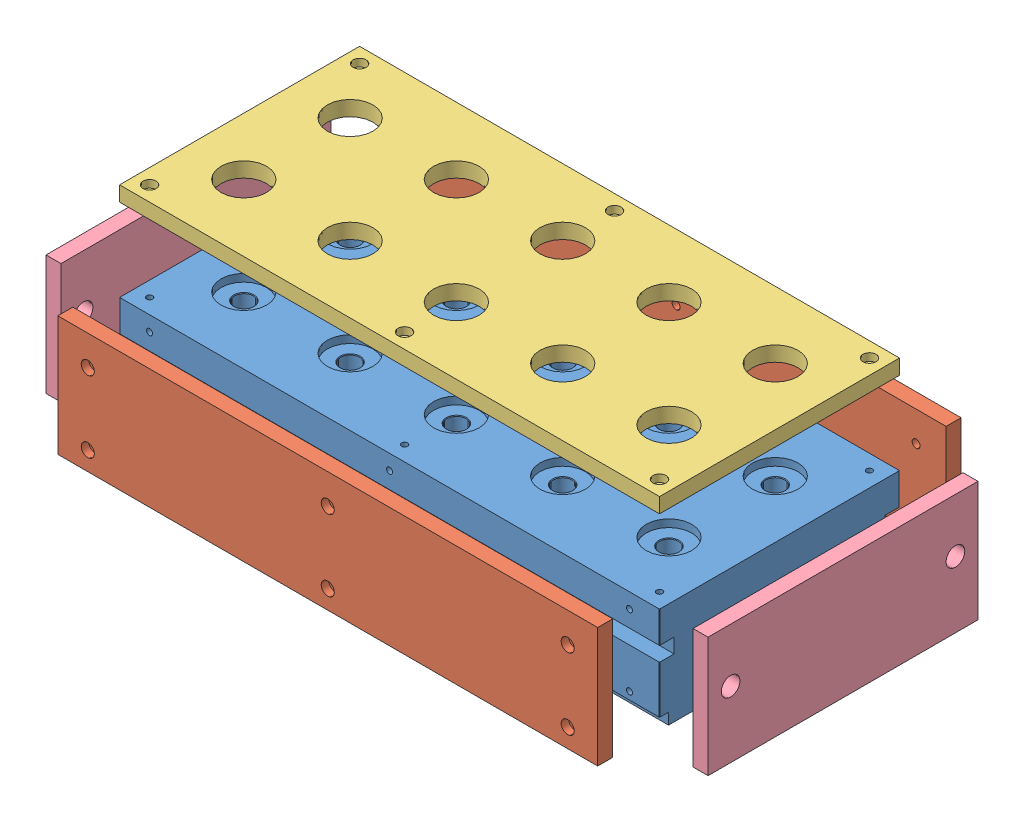
SolidWorks assembly htrblockassem1, configuration Default. Lengths in mm.
Overall size (560.62 171.47 307.71).
6 component instances, 4 part files, 10 mates.
Components (placement in the parent):
- heatblk1-1: heatblk1 [Default] at origin size (457.2 88.9 203.2)
- sideinsul1-1: sideinsul1 [Default] at (0 -50.8 153.9476) x (1 0 0) z (0 -1 0) size (457.2 12.7 101.6)
- sideinsul1-2: sideinsul1 [Default] at (0 -50.8 -153.7667) x (-1 0 0) z (0 -1 0) size (457.2 12.7 101.6)
- topinsul1-1: topinsul1 [Default] at (0 69.865 0) size (457.2 12.7 203.2)
- endisul1-1: endisul1 [Default] at (282.3898 -50.8 0) size (12.7 101.6 228.6)
- endisul1-2: endisul1 [Default] at (-265.5266 -50.8 0) size (12.7 101.6 228.6)
Mates (geometry in assembly coordinates):
- Coincident1: coincident aligned: plane of heatblk1-1 through (228.6 -101.6 -101.6) normal (1 0 0); plane of topinsul1-1 through (228.6 57.165 -101.6) normal (1 0 0)
- Coincident2: coincident aligned: plane of heatblk1-1 through (228.6 -101.6 101.6) normal (0 0 1); plane of topinsul1-1 through (228.6 57.165 101.6) normal (0 0 1)
- Coincident3: coincident aligned: plane of sideinsul1-2 through (228.6 0 -141.0667) normal (1 0 0); plane of topinsul1-1 through (228.6 57.165 -101.6) normal (1 0 0)
- Coincident4: coincident aligned: plane of heatblk1-1 through (0 -101.6 0) normal (0 -1 0); plane of sideinsul1-2 through (-228.6 -101.6 -141.0667) normal (0 -1 0)
- Coincident5: coincident aligned: plane of sideinsul1-1 through (228.6 -101.6 141.2476) normal (0 -1 0); plane of heatblk1-1 through (0 -101.6 0) normal (0 -1 0)
- Coincident8: coincident aligned: plane of heatblk1-1 through (228.6 -101.6 -101.6) normal (1 0 0); plane of sideinsul1-1 through (228.6 0 141.2476) normal (1 0 0)
- Coincident9: coincident aligned: plane of heatblk1-1 through (0 -101.6 0) normal (0 -1 0); plane of endisul1-1 through (269.6898 -101.6 -114.3) normal (0 -1 0)
- Coincident10: coincident aligned: plane of heatblk1-1 through (0 -101.6 0) normal (0 -1 0); plane of endisul1-2 through (-278.2266 -101.6 -114.3) normal (0 -1 0)
- Coincident11: coincident aligned: plane of endisul1-1 through (269.6898 0 -114.3) normal (0 0 -1); plane of endisul1-2 through (-278.2266 0 -114.3) normal (0 0 -1)
- Width1: width anti-aligned: plane of endisul1-2 through (-278.2266 0 -114.3) normal (0 0 -1); plane of heatblk1-1 through (-278.2266 0 114.3) normal (0 0 1); plane of endisul1-2 through (228.6 -101.6 101.6) normal (0 0 1); plane of heatblk1-1 through (228.6 -101.6 -101.6) normal (0 0 -1)
